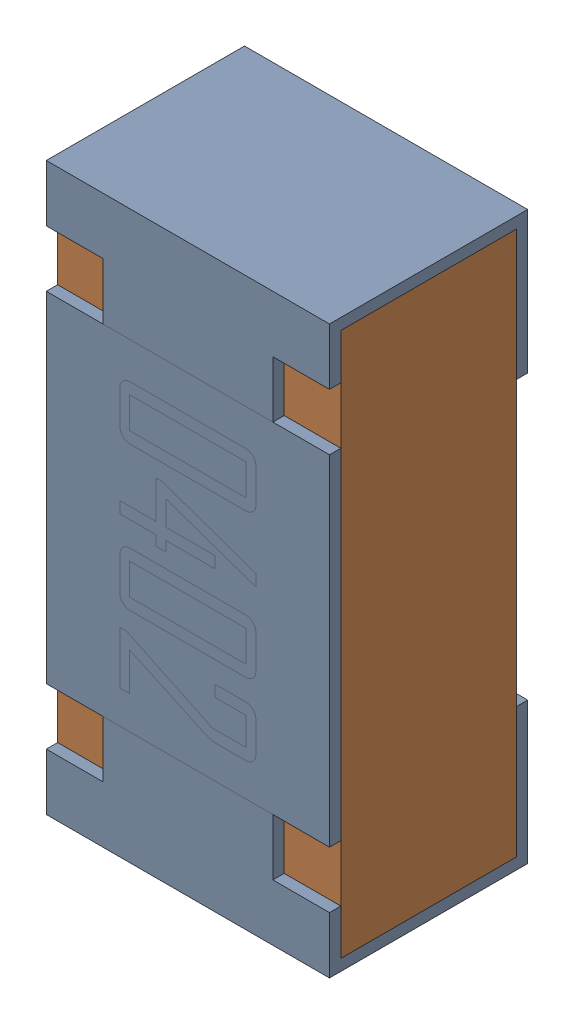
SolidWorks assembly R1, configuration Default. Lengths in mm.
Overall size (0.5 1 0.35).
3 component instances, 2 part files, 0 mates.
Components (placement in the parent):
- R1-subassembly-1-1: R1-subassembly-1 [Default] at (-13 0.0001 0) x (0 -1 0) z (-1 0 0) size (1 0.35 0.5)
  - 0402 resistor-1: 0402 resistor [Default] at origin size (1 0.35 0.5)
  - 0402 resistor-1-1: 0402 resistor-1 [Default] at origin size (0.96 0.31 0.5)
